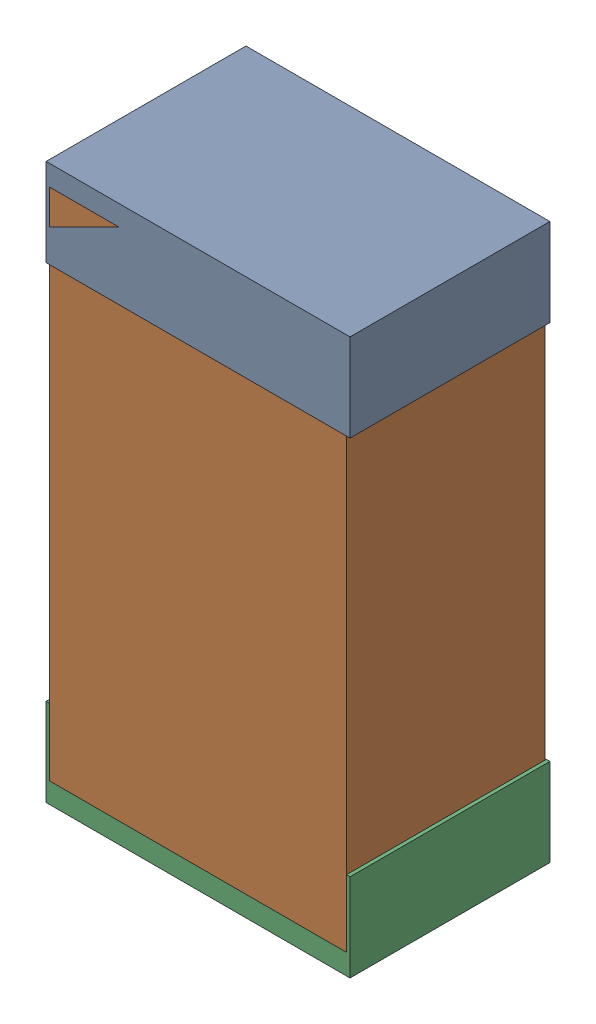
SolidWorks assembly R12Kanaloa_v2.0.0_Power, configuration Default. Lengths in mm.
Overall size (1.3 2.38 0.85).
6 component instances, 2 part files, 0 mates.
Components (placement in the parent):
- 330415056-1: 330415056 [Default] at (125.65 39.225 -1.9574) size (1.3 0.38 0.85)
  - Extruded_2-1: Extruded_2 [Default] at origin size (1.3 0.38 0.85)
- 352877008-1: 352877008 [Default] at (125.65 38.225 -1.9524) size (1.27 2.2 0.85)
  - Extruded_3-1: Extruded_3 [Default] at origin size (1.27 2.2 0.85)
- 330415056-2: 330415056 [Default] at (125.65 37.225 -1.9574) size (1.3 0.38 0.85)
  - Extruded_2-1: Extruded_2 [Default] at origin size (1.3 0.38 0.85)
